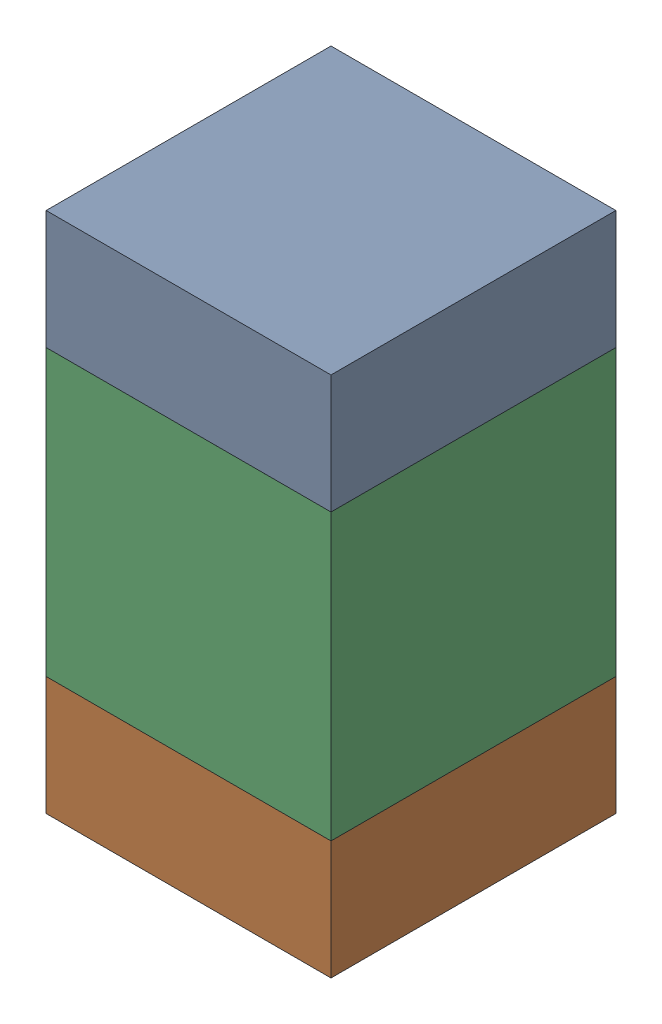
SolidWorks assembly C107_1PCB, configuration Default. Lengths in mm.
Overall size (0.6 1.1 0.6).
6 component instances, 2 part files, 0 mates.
Components (placement in the parent):
- 854785296-1: 854785296 [Default] at (100 109.425 0) size (0.6 0.25 0.6)
  - Extruded_10-1: Extruded_10 [Default] at origin size (0.6 0.25 0.6)
- 854785296-2: 854785296 [Default] at (100 108.575 0) size (0.6 0.25 0.6)
  - Extruded_10-1: Extruded_10 [Default] at origin size (0.6 0.25 0.6)
- 761606048-1: 761606048 [Default] at (100 109 0) size (0.6 0.6 0.6)
  - Extruded_9-1: Extruded_9 [Default] at origin size (0.6 0.6 0.6)
